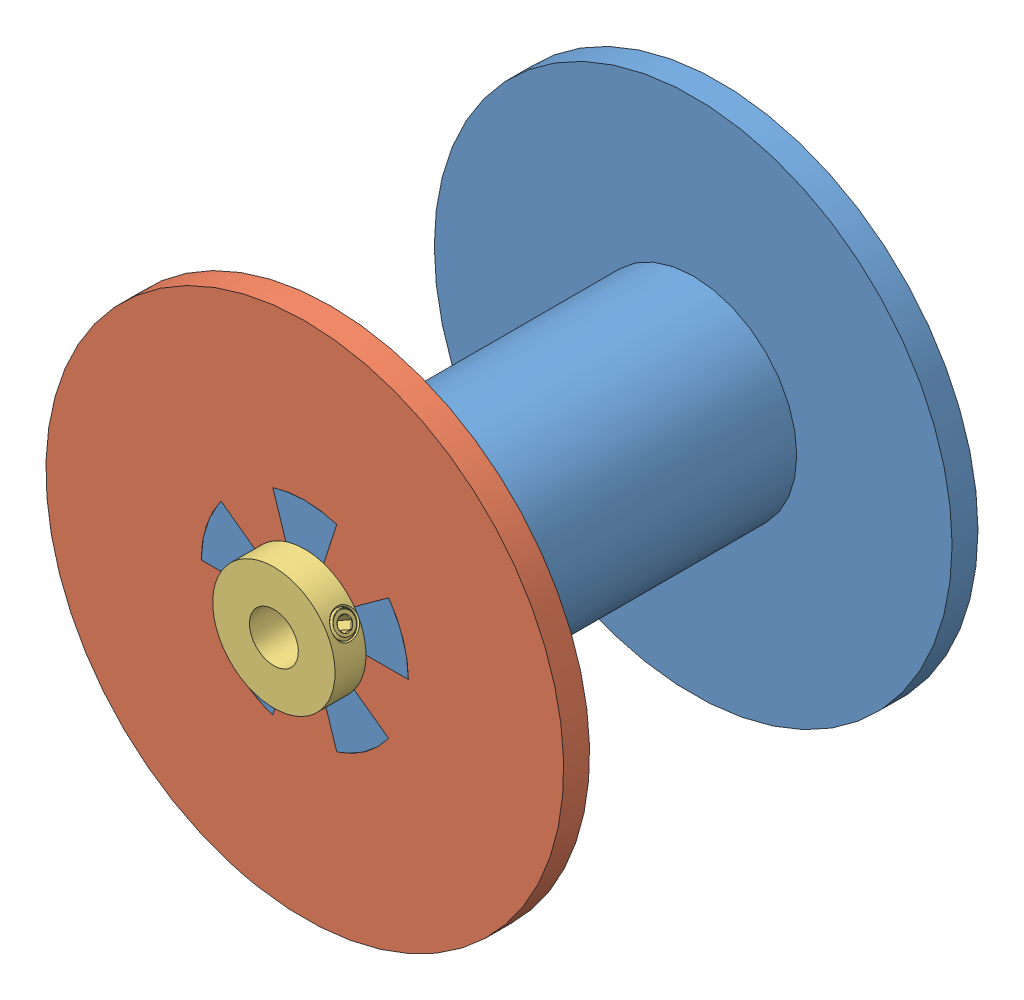
SolidWorks assembly test, configuration Default. Lengths in mm.
Overall size (76.67 76.67 54.59).
3 component instances, 3 part files, 5 mates.
Components (placement in the parent):
- spool-1: spool [Default] at (19.4579 29.3863 53.5304) size (63.5 63.5 50.8)
- spool flange-1: spool flange [Default] at (19.4579 29.3863 75.7554) x (0.971862 -0.235552 0) z (-0.235552 -0.971862 0) size (63.5 3.17 63.5)
- 9939T314_Vibrate-Damping Precision Flexible Shaft Coupling-1: 9939T314_Vibrate-Damping Precision Flexible Shaft Coupling [9939T314] at (19.4579 29.3863 71.8204) x (-0.488422 0.872608 0) z (0 0 -1) size (15 15.22 13.49)
Mates (geometry in assembly coordinates):
- Concentric1: concentric aligned: cylinder of spool-1 through (19.4579 29.3863 28.1304) axis (0 0 -1) radius 31.75; cylinder of spool flange-1 through (19.4579 29.3863 78.9304) axis (0 0 -1) radius 31.75
- Concentric2: concentric aligned: cylinder of spool-1 through (19.4579 29.3863 28.1304) axis (0 0 -1) radius 12.7; cylinder of 9939T314_Vibrate-Damping Precision Flexible Shaft Coupling-1 through (19.4579 29.3863 82.7204) axis (0 0 -1) radius 3
- Coincident3: coincident aligned: plane of spool-1 through (19.4579 38.9113 78.9304) normal (0 0 1); plane of spool flange-1 through (19.4579 29.3863 78.9304) normal (0 0 1)
- Coincident4: coincident anti-aligned: plane of spool-1 through (19.4579 29.3863 75.7554) normal (0.951057 -0.309017 0); plane of spool flange-1 through (15.5334 17.3079 78.9304) normal (-0.951057 0.309017 0)
- Coincident5: coincident anti-aligned: plane of spool-1 through (19.4579 29.3863 75.1204) normal (0 0 1); plane of 9939T314_Vibrate-Damping Precision Flexible Shaft Coupling-1 through (19.4579 29.3863 75.1204) normal (0 0 -1)
